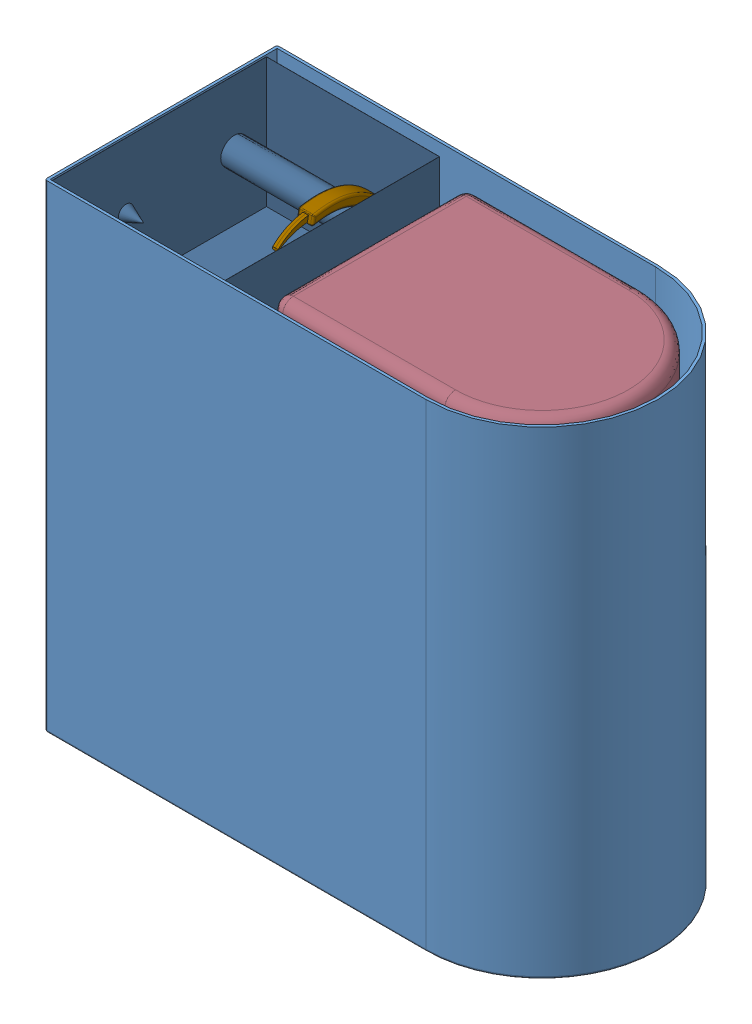
SolidWorks assembly Assem1, configuration Default. Lengths in mm.
Overall size (523.11 442.5 365.37).
16 component instances, 13 part files, 17 mates.
Components (placement in the parent):
- part2-1: part2 [Default] at (-127.7946 -150.1043 24.4799) size (523.11 442.5 365.37)
- motor_-1: motor_ [Default] at (-74.3561 -159.974 62.112) x (0 -1 0) z (-0.62538 0 0.78032) size (147 148.97 146.3)
- vesselassembly-1: vesselassembly [Default] at (-70.3829 -64.9855 -146.7994) x (0.98472 0 -0.174147) z (0.174147 0 0.98472) size (217.94 123.92 217.94)
  - finalVessel-1: finalVessel [Default] at (92.7403 96.7089 136.3589) size (190.28 95.67 190.28)
    - jaali-1: jaali [Default] at (-80.6305 -22.3277 39.7198) size (190.28 54 190.28)
    - part0-1: part0 [Default] at (-164.8961 18.0262 39.7198) x (-1 0 0) z (0 0 -1) size (167.08 119.55 129.81)
    - blade-1: blade [Default] at (-80.6305 -33.3277 39.7198) x (0.965204 0 -0.261496) z (0.261496 0 0.965204) size (119.96 5 119.96)
    - base0-1: base0 [Default] at (-80.6305 -34.3277 39.7198) size (145.84 25.29 145.84)
    - base1-1: base1 [Default] at (-80.6305 -35.3277 39.7198) size (137.75 106.62 110)
  - top circle-1: top circle [Default] at (12.1098 127.9329 176.0787) x (0.995326 0 0.096576) z (-0.096576 0 0.995326) size (199.6 57.37 199.6)
- cutter assembly-1: cutter assembly [Default] at (-419.5234 233.7139 -27.6318) x (0 -1 0) z (0 0 1) size (120.1 160.2 200.2)
  - cutter-1: cutter [Default] at (5.8963 166.6915 -12.9883) x (-0.177196 0 0.984176) z (0.984176 0 0.177196) size (110.26 22.55 63.98)
  - Part4cutter-1: Part4cutter [Default] at (65.5227 121.8287 60.492) x (0 1 0) z (0 0 1) size (160.2 120.1 200.2)
- conveyor-1: conveyor [Default] at (-226.16 80.5726 -106.4978) size (202 42 160)
- box1-1: box1 [Default] at (-247.8121 -151.3984 11.6127) size (220 180 200)
- box2-1: box2 [Default] at (-87.7946 163.8313 24.4799) size (250 120 180)
Mates (geometry in assembly coordinates):
- Coincident11: coincident anti-aligned: plane of part2-1 through (-27.7946 -150.1043 24.4799) normal (0 1 0); plane of motor_-1 through (21.3656 -150.1043 63.8788) normal (0 -1 0)
- Concentric1: concentric anti-aligned: circle of part2-1; cylinder of motor_-1 through (-27.7946 -340.5066 24.4799) axis (0 -1 0) radius 73.15
- Parallel2: parallel anti-aligned: plane of motor_-1 through (-27.7946 -5.6043 24.4799) normal (0 1 0); plane of vesselassembly-1/finalVessel-1/base1-1 through (23.4108 -5.6043 15.4242) normal (0 -1 0)
- Coincident15: coincident anti-aligned: plane of motor_-1 through (-27.7946 -5.6043 24.4799) normal (0 1 0); plane of vesselassembly-1/finalVessel-1/base1-1 through (23.4108 -5.6043 15.4242) normal (0 -1 0)
- Concentric2: concentric aligned: circle of motor_-1; circle of vesselassembly-1/finalVessel-1/base1-1
- Coincident23: coincident anti-aligned: plane of part2-1 through (-377.7946 289.8957 -80.5201) normal (1 0 0); plane of cutter assembly-1/Part4cutter-1 through (-377.7946 288.1912 -70.5201) normal (-1 0 0)
- Parallel7: parallel anti-aligned: plane of part2-1 through (-377.7946 289.8957 -80.5201) normal (0 0 1); plane of cutter assembly-1/Part4cutter-1 through (-217.6946 288.1912 -70.6201) normal (0 0 -1)
- Coincident25: coincident aligned: plane of part2-1 through (-377.7946 289.8957 129.4799) normal (0 0 -1); plane of cutter assembly-1/Part4cutter-1 through (-377.6946 288.1912 129.4799) normal (0 0 -1)
- Parallel8: parallel aligned: line of part2-1 through (-27.7946 289.8957 -80.5201) axis (-1 0 0); line of cutter assembly-1/Part4cutter-1 through (-217.6946 288.1912 -70.5201) axis (-1 0 0)
- Parallel9: parallel aligned: line of part2-1 through (-27.7946 289.8957 -80.5201) axis (-1 0 0); line of cutter assembly-1/Part4cutter-1 through (-217.6946 288.1912 -70.5201) axis (-1 0 0)
- Parallel10: parallel aligned: plane of cutter assembly-1/Part4cutter-1 through (-297.6946 168.1912 32.8601) normal (0 1 0); plane of conveyor-1 through (-157.0021 121.5726 92.7057) normal (0 1 0)
- Parallel11: parallel anti-aligned: plane of part2-1 through (-377.7946 289.8957 -80.5201) normal (0 0 1); plane of conveyor-1 through (-157.0021 100.5726 -67.2943) normal (0 0 -1)
- Parallel12: parallel aligned: plane of part2-1 through (-377.7946 289.8957 131.9799) normal (0 0 1); plane of conveyor-1 through (-317.0021 100.5726 92.7057) normal (0 0 1)
- Parallel13: parallel aligned: plane of part2-1 through (-380.2946 289.8957 -80.5201) normal (-1 0 0); plane of box1-1 through (-357.8121 28.6016 -88.3873) normal (-1 0 0)
- Parallel14: parallel aligned: plane of part2-1 through (-377.7946 289.8957 131.9799) normal (0 0 1); plane of box1-1 through (-357.8121 28.6016 111.6127) normal (0 0 1)
- Parallel15: parallel aligned: plane of cutter assembly-1/Part4cutter-1 through (-217.6946 288.1912 129.4799) normal (-1 0 0); plane of box2-1 through (-187.7946 283.8313 -65.5201) normal (-1 0 0)
- Concentric3: concentric anti-aligned: circle of part2-1; cylinder of box2-1 through (-27.7946 283.8313 24.4799) axis (0 -1 0) radius 90
